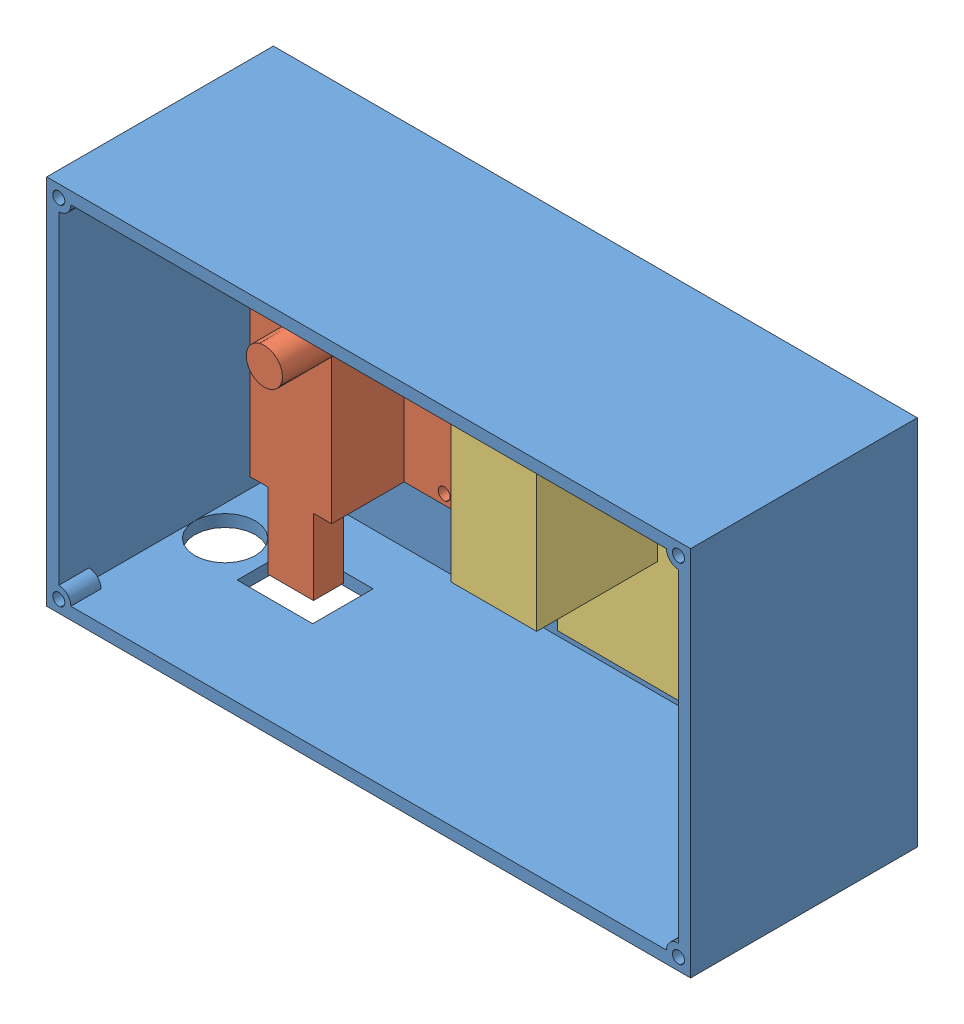
SolidWorks assembly ControllerAssem, configuration Default. Lengths in mm.
Overall size (213 123 75).
3 component instances, 3 part files, 6 mates.
Components (placement in the parent):
- ControllerBase-1: ControllerBase [Default] at (50.2766 86.6587 122.6506) size (213 123 75)
- OpenCM-1: OpenCM [Default] at (-15.4734 89.1587 128.6506) size (68.5 91.5 55)
- PowerBoard-1: PowerBoard [Default] at (95.7766 87.6587 128.6506) size (100 104 42)
Mates (geometry in assembly coordinates):
- Coincident1: coincident aligned: circle of ControllerBase-1; cylinder of OpenCM-1 through (-42.2234 119.1587 128.6506) axis (0 0 1) radius 2
- Concentric1: concentric aligned: circle of ControllerBase-1; cylinder of OpenCM-1 through (11.2766 119.1587 128.6506) axis (0 0 1) radius 2
- Coincident3: coincident anti-aligned: plane of ControllerBase-1 through (11.2766 119.1587 128.6506) normal (0 0 1); plane of OpenCM-1 through (-15.4734 89.1587 128.6506) normal (0 0 -1)
- Concentric2: concentric aligned: circle of ControllerBase-1; circle of PowerBoard-1
- Concentric3: concentric aligned: circle of ControllerBase-1; circle of PowerBoard-1
- Coincident4: coincident anti-aligned: plane of ControllerBase-1 through (51.7766 50.6587 128.6506) normal (0 0 1); plane of PowerBoard-1 through (95.7766 87.6587 128.6506) normal (0 0 -1)
